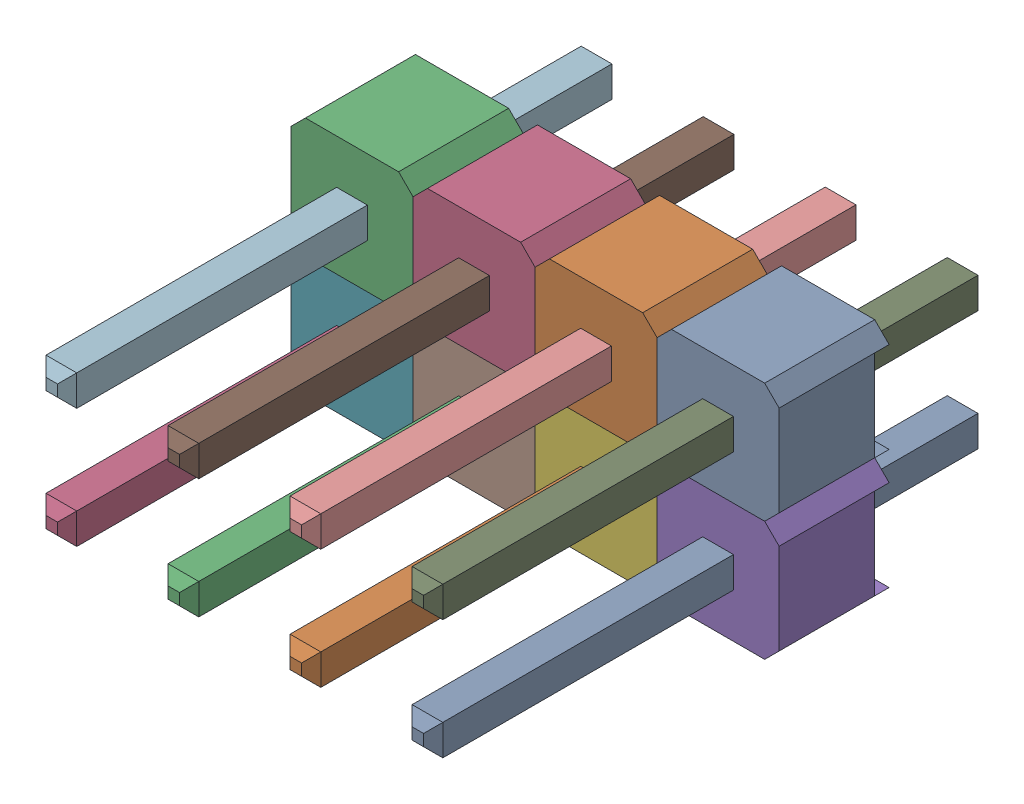
SolidWorks assembly User Library-2.54mm Male Header (4x2), configuration 默认. Lengths in mm.
Overall size (10.16 4.98 11.54).
6 component instances, 2 part files, 0 mates.
Components (placement in the parent):
- User Library-Header_Male_4Pin-1: User Library-Header_Male_4Pin [默认] at (-35.6012 -1.8987 15.2958) size (10.16 2.49 11.54)
  - User Library-Header_Male_4Pin_PinArray-1: User Library-Header_Male_4Pin_PinArray [默认] at origin size (8.26 0.64 11.54)
  - User Library-Header_Male_4Pin_BodyArray-1: User Library-Header_Male_4Pin_BodyArray [默认] at origin size (10.16 2.49 2.29)
- User Library-Header_Male_4Pin-1-1: User Library-Header_Male_4Pin-1 [默认] at (-35.6012 0.5913 15.2958) size (10.16 2.49 11.54)
  - User Library-Header_Male_4Pin_PinArray-1: User Library-Header_Male_4Pin_PinArray [默认] at origin size (8.26 0.64 11.54)
  - User Library-Header_Male_4Pin_BodyArray-1: User Library-Header_Male_4Pin_BodyArray [默认] at origin size (10.16 2.49 2.29)
